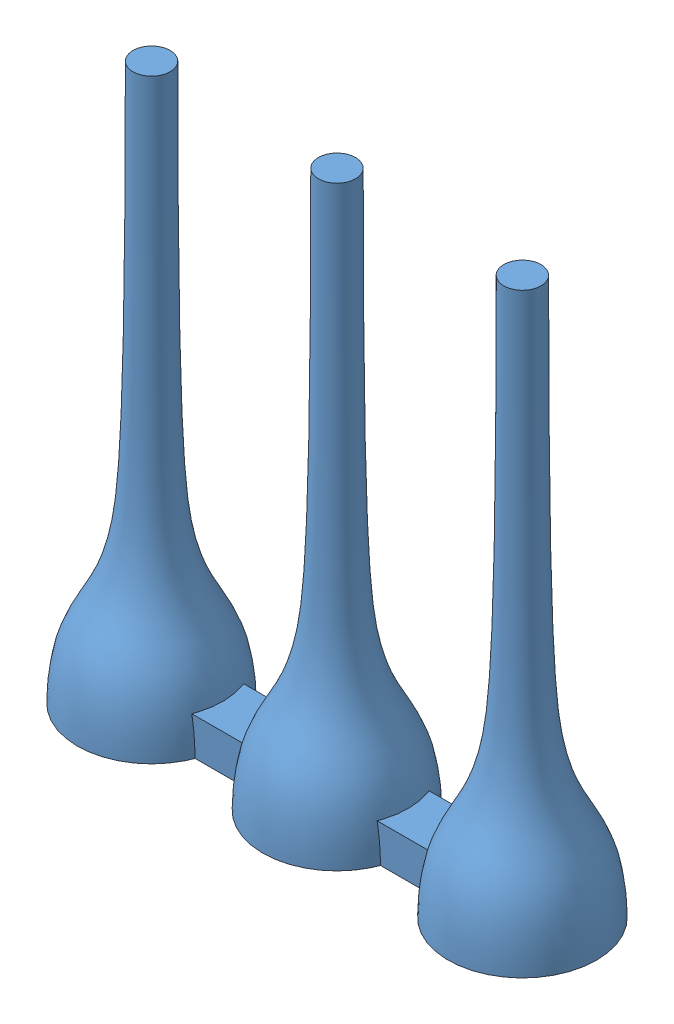
SolidWorks assembly connected, configuration Default. Lengths in mm.
Overall size (14.51 15 7.22).
3 component instances, 3 part files, 3 mates.
Components (placement in the parent):
- convex_cone2-1: convex_cone2 [Default] at (4.9529 0 -0.6844) size (4 15 4) (hidden)
- connector-1: connector [Default] at (4.7617 1.5106 1.8839) size (10 1 1.4) (hidden)
- convex_cone-2: convex_cone [Default] at (-0.2383 1.0106 2.8839) x (0.990587 0 0.136884) z (-0.136884 0 0.990587) size (13.91 15 5.37)
Mates (geometry in assembly coordinates):
- Coincident1: coincident: line of connector-1 through (-0.2383 2.0106 3.5839) axis (0 0 -1); line of convex_cone-2 through (-0.2383 1.0106 2.8839) axis (0 0 -1)
- Coincident3: coincident aligned: plane of connector-1 through (-0.2383 1.0106 3.8839) normal (0 -1 0); plane of convex_cone-2 through (-0.2383 1.0106 2.8839) normal (0 -1 0)
- Distance1: distance = 1 mm: point of connector-1; point of convex_cone-2
